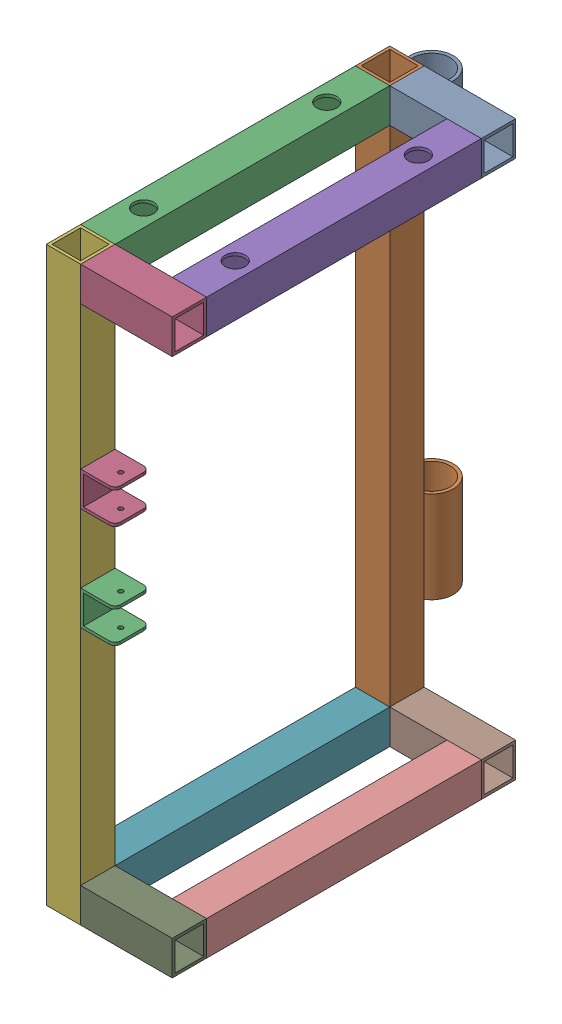
SolidWorks assembly GE-16036_ASM, configuration Default. Lengths in mm.
Overall size (144.78 635 432.44).
16 component instances, 7 part files, 0 mates.
Components (placement in the parent):
- GE-16036-03-1: GE-16036-03 [Default] at origin size (101.6 38.1 38.1)
- GE-16036-02-1: GE-16036-02 [Default] at (-69.85 -298.45 0) x (0 1 0) z (1 0 0) size (635 38.1 38.1)
- GE-16036-05-1: GE-16036-05 [Default] at (-69.85 0 171.45) x (0 0 1) z (1 0 0) size (304.8 38.1 38.1)
- GE-16036-03-2: GE-16036-03 [Default] at (0 0 342.9) x (1 0 0) z (0 1 0) size (101.6 38.1 38.1)
- GE-16036-05-2: GE-16036-05 [Default] at (31.75 0 171.45) x (0 0 -1) z (-1 0 0) size (304.8 38.1 38.1)
- GE-16036-02-2: GE-16036-02 [Default] at (-69.85 -298.45 342.9) x (0 1 0) z (1 0 0) size (635 38.1 38.1)
- GE-16036-04-1: GE-16036-04 [Default] at (-69.85 -596.9 171.45) x (0 0 1) z (-1 0 0) size (304.8 38.1 38.1)
- GE-16036-03-3: GE-16036-03 [Default] at (0 -596.9 0) size (101.6 38.1 38.1)
- GE-16036-03-4: GE-16036-03 [Default] at (0 -596.9 342.9) size (101.6 38.1 38.1)
- GE-16036-04-2: GE-16036-04 [Default] at (31.75 -596.9 171.45) x (0 0 1) z (-1 0 0) size (304.8 38.1 38.1)
- GE-16036-07-1: GE-16036-07 [Default] at (-69.85 -449.2625 -22.225) size (12.7 101.6 3.17)
- GE-16036-07-2: GE-16036-07 [Default] at (-69.85 -57.15 -22.225) size (12.7 101.6 3.17)
- GE-16036-06-1: GE-16036-06 [Default] at (-69.85 -57.15 -46.355) x (0 0 1) z (-1 0 0) size (48.26 101.6 48.26)
- GE-16036-06-2: GE-16036-06 [Default] at (-69.85 -449.2625 -46.355) x (0 0 1) z (-1 0 0) size (48.26 101.6 48.26)
- GE-13036-01-1: GE-13036-01 [Default] at (-50.8 -311.15 342.9) x (0 0 1) z (-1 0 0) size (38.1 38.1 38.1)
- GE-13036-01-2: GE-13036-01 [Default] at (-50.8 -196.85 342.9) x (0 0 1) z (-1 0 0) size (38.1 38.1 38.1)
